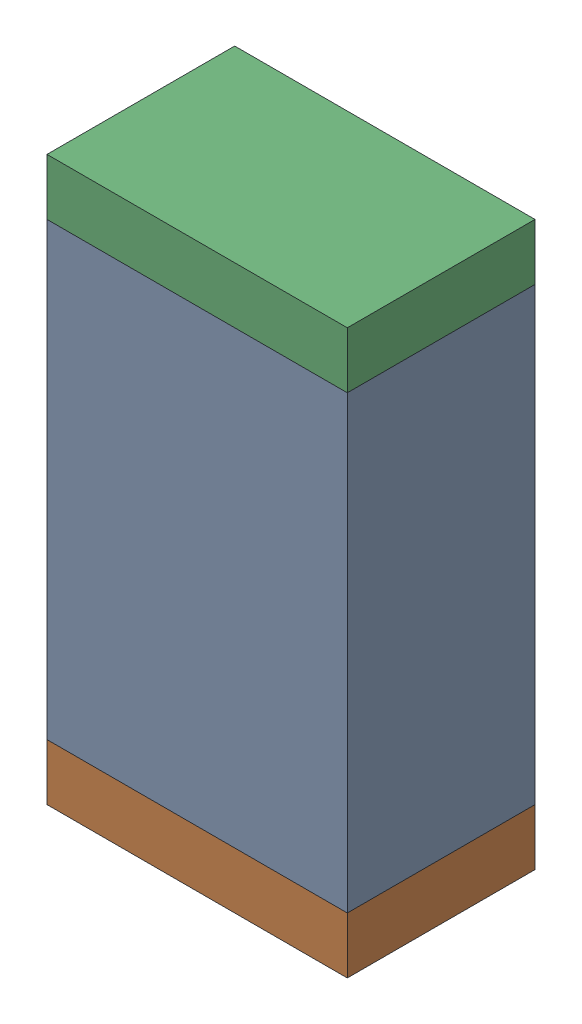
SolidWorks assembly R66, configuration Default. Lengths in mm.
Overall size (0.8 1.5 0.5).
6 component instances, 2 part files, 0 mates.
Components (placement in the parent):
- 810156976-1: 810156976 [Default] at (110 73.75 0) size (0.8 1.2 0.5)
  - Extruded_6-1: Extruded_6 [Default] at origin size (0.8 1.2 0.5)
- 810156592-1: 810156592 [Default] at (110 73.075 0) size (0.8 0.15 0.5)
  - Extruded_7-1: Extruded_7 [Default] at origin size (0.8 0.15 0.5)
- 810156592-2: 810156592 [Default] at (110 74.425 0) size (0.8 0.15 0.5)
  - Extruded_7-1: Extruded_7 [Default] at origin size (0.8 0.15 0.5)
